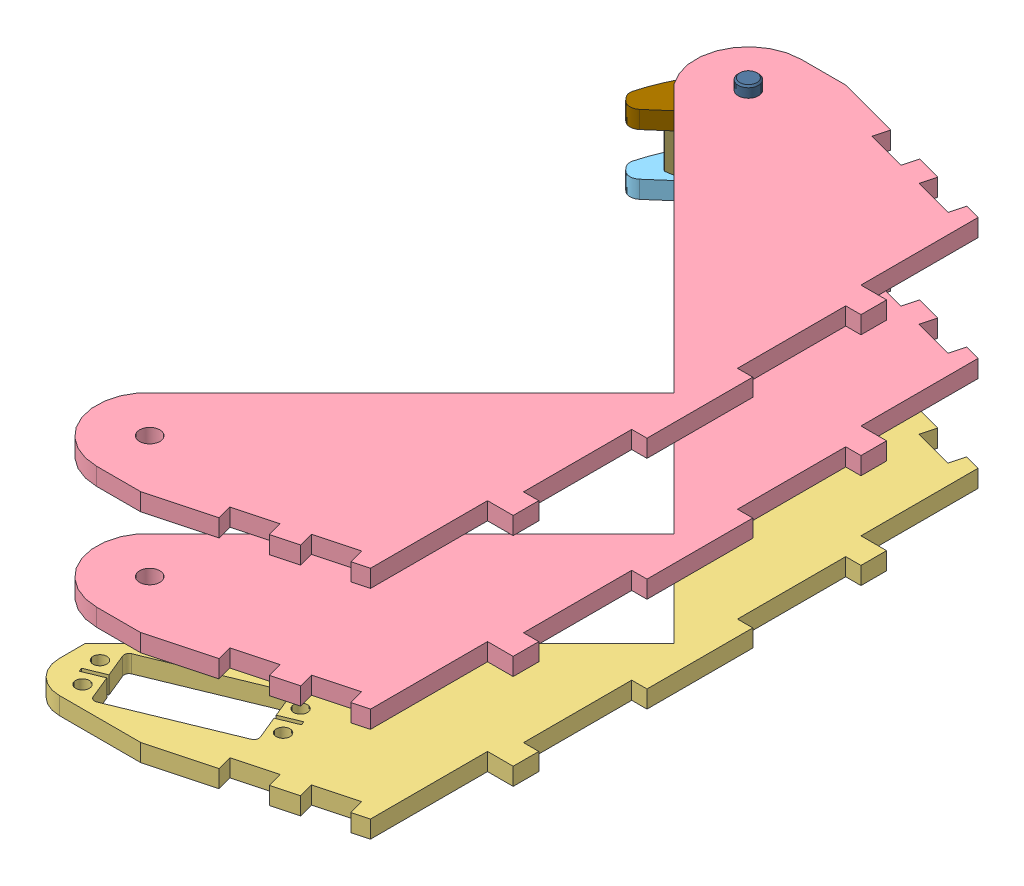
SolidWorks assembly Gripper Assm rA.01, configuration Default. Lengths in mm.
Overall size (128.06 105.71 236.15).
20 component instances, 15 part files, 50 mates.
Components (placement in the parent):
- 1718 GLYPH BLACK-1: 1718 GLYPH BLACK [Default] at (-76.2 0 0) size (152.4 152.4 152.4) (hidden)
- 1718 GLYPH BLACK-2: 1718 GLYPH BLACK [Default] at (-152.4 0 0) x (0.707107 0 0.707107) z (-0.707107 0 0.707107) size (152.4 152.4 152.4) (hidden)
- Grabber Paddle-1: Grabber Paddle [Default] at origin
- TETRIX_739197_SERVO_2012-1: TETRIX_739197_SERVO_2012 [Default] at (-7.184 35.6 -93.4511) x (-0.380109 0 0.924942) z (-0.924942 0 -0.380109) size (20 43.2 56.76)
- 8699-17-307 Gripper Mount Structure-1: 8699-17-307 Gripper Mount Structure [Default] at origin
- Tetrix Servo Hub Metal Light Duty-1: Tetrix Servo Hub Metal Light Duty [Default] at (-7.184 55.1 -93.4511) size (22 6.2 22)
- 8699-17-314 Gripper Strut ServoMnt-1: 8699-17-314 Gripper Strut ServoMnt [Default] at (63.1261 38.1 0) size (100 5.46 220)
- 8699-17-315 Gripper Strut Axle-1: 8699-17-315 Gripper Strut Axle [Default] at (63.1261 67.8 0) size (94.86 5.46 220)
- 8699-17-315 Gripper Strut Axle-2: 8699-17-315 Gripper Strut Axle [Default] at (63.1261 105.9 0) size (94.86 5.46 220)
- 8699-17-316 Gripper Right Servoed-1: 8699-17-316 Gripper Right Servoed [Default] at (-7.184 55.1 -93.4511) size (63.25 5.46 43.7)
- 90631A007 Hex Nut 6-32 Nyloc LoS-1: 90631A007 Hex Nut 6-32 Nyloc LoS [90631A007] at (-7.184 60.561 -101.4511) size (7.94 4.37 9.17)
- tetrix_739097 Screw SHC 6-32 0.50Lg-1: tetrix_739097 Screw SHC 6-32 0.50Lg [Default] at (-7.184 53.1 -101.4511) x (-1 0 0) z (0 0 1) size (5.74 16.21 5.74)
- Washer .31 id-1: Washer .31 id [Default] at (-7.184 73.261 -93.4511) size (22.17 0.71 22.17)
- 8699-17-317 rC Gripper Right Axled-3: 8699-17-317 rC Gripper Right Axled [Default] at (-7.184 73.9722 -93.4511) size (63.25 5.46 43.7)
- Washer .31 id-2: Washer .31 id [Default] at (-7.184 105.1888 -93.4511) size (22.17 0.71 22.17)
- Washer .31 id-3: Washer .31 id [Default] at (-7.184 79.4332 -93.4511) size (22.17 0.71 22.17)
- 8699-17-318 Shaft - Gripper Grooved-1: 8699-17-318 Shaft - Gripper Grooved [Default] at (-7.184 57.561 -93.4511) size (6.35 57.15 6.35)
- 8699-17-319 Grippers Dowel Conn-1: 8699-17-319 Grippers Dowel Conn [Default] at (-28.0465 60.561 -108.5448) size (15.88 13.41 15.88)
- 8699-17-324 Grippers Dowel Conn Front-1: 8699-17-324 Grippers Dowel Conn Front [Default] at (-44.5973 60.561 -115.7104) x (0.917686 0 0.397307) z (-0.397307 0 0.917686) size (15.88 13.41 15.72)
- 8699-17-317 rC Gripper Right Axled-2: 8699-17-317 rC Gripper Right Axled [Default] at (-7.184 111.361 -93.4511) x (0.997645 0 -0.068586) z (0.068586 0 0.997645) size (63.25 5.46 43.7) (hidden)
Mates (geometry in assembly coordinates):
- Coincident1: coincident aligned: plane of 1718 GLYPH BLACK-1 through (-76.2 0 0) normal (0 1 0); plane of assembly through (0 0 0) normal (0 1 0)
- Coincident2: coincident aligned: plane of 1718 GLYPH BLACK-1 through (0 0 76.2) normal (1 0 0); plane of assembly through (0 0 0) normal (1 0 0)
- Coincident3: coincident aligned: plane of 1718 GLYPH BLACK-1 through (-76.2 0 0) normal (0 0 1); plane of assembly through (0 0 0) normal (0 0 1)
- Coincident4: coincident aligned: plane of 1718 GLYPH BLACK-1 through (-76.2 152.4 0) normal (0 1 0); plane of 1718 GLYPH BLACK-2 through (-152.4 152.4 0) normal (0 1 0)
- Coincident5: coincident: point of 1718 GLYPH BLACK-2; plane of assembly
- Angle1: planar angle = 0.785398 rad aligned: plane of 1718 GLYPH BLACK-2 through (-152.4 0 0) normal (0.707107 0 0.707107); plane of assembly through (0 0 0) normal (1 0 0)
- Coincident8: coincident: plane of 1718 GLYPH BLACK-1 through (-152.4 0 -76.2) normal (-1 0 0); point of 1718 GLYPH BLACK-2
- Concentric1: concentric: cylinder of TETRIX_739197_SERVO_2012-1 through (-7.184 52.2 -93.4511) axis (0 -1 0) radius 3; point of assembly
- Coincident10: coincident aligned: plane of TETRIX_739197_SERVO_2012-1 through (-7.184 0 -90.4193) normal (0 1 0); plane of assembly through (0 0 0) normal (0 1 0)
- Coincident11: coincident anti-aligned: plane of TETRIX_739197_SERVO_2012-1 through (-7.184 48.9 -93.4511) normal (0 1 0); plane of Tetrix Servo Hub Metal Light Duty-1 through (-11.584 48.9 -93.4511) normal (0 -1 0)
- Concentric2: concentric aligned: cylinder of TETRIX_739197_SERVO_2012-1 through (-7.184 52.2 -93.4511) axis (0 -1 0) radius 3; cylinder of Tetrix Servo Hub Metal Light Duty-1 through (-7.184 55.1 -93.4511) axis (0 -1 0) radius 1.75
- Distance1: distance = 38.1 mm aligned: plane of 8699-17-314 Gripper Strut ServoMnt-1 through (63.1261 38.1 0) normal (0 1 0); plane of assembly through (0 0 0) normal (0 1 0)
- Parallel1: parallel aligned: plane of 8699-17-314 Gripper Strut ServoMnt-1 through (63.1261 38.1 0) normal (1 0 0); plane of assembly through (0 0 0) normal (1 0 0)
- Angle2: planar angle = 1.960711 rad aligned: plane of TETRIX_739197_SERVO_2012-1 through (-7.184 35.6 -93.4511) normal (-0.380109 0 0.924942); plane of assembly through (0 0 0) normal (1 0 0)
- Coincident17: coincident anti-aligned: plane of TETRIX_739197_SERVO_2012-1 through (22.288 38.1 -72.8253) normal (0 1 0); plane of 8699-17-314 Gripper Strut ServoMnt-1 through (63.1261 38.1 0) normal (0 -1 0)
- Coincident18: coincident aligned: plane of 8699-17-314 Gripper Strut ServoMnt-1 through (71.1261 43.561 -58.293) normal (1 0 0); plane of 8699-17-315 Gripper Strut Axle-1 through (71.1261 73.261 -58.293) normal (1 0 0)
- Distance2: distance = 12.7 mm anti-aligned: plane of 8699-17-315 Gripper Strut Axle-1 through (-7.184 67.8 93.4511) normal (0 -1 0); plane of Tetrix Servo Hub Metal Light Duty-1 through (-18.184 55.1 -93.4511) normal (0 1 0)
- Coincident20: coincident aligned: plane of 8699-17-314 Gripper Strut ServoMnt-1 through (-28.8739 43.561 -110) normal (0 0 -1); plane of 8699-17-315 Gripper Strut Axle-1 through (-7.184 73.261 -110) normal (0 0 -1)
- Coincident21: coincident aligned: plane of Tetrix Servo Hub Metal Light Duty-1 through (-18.184 55.1 -93.4511) normal (0 1 0); plane of 8699-17-316 Gripper Right Servoed-1 through (-7.184 55.1 -93.4511) normal (0 1 0)
- Concentric3: concentric aligned: cylinder of Tetrix Servo Hub Metal Light Duty-1 through (-7.184 55.1 -93.4511) axis (0 -1 0) radius 1.75; line of 8699-17-316 Gripper Right Servoed-1 through (-7.184 105.1 -93.4511) axis (0 -1 0)
- Parallel3: parallel aligned: plane of 8699-17-316 Gripper Right Servoed-1 through (-7.184 55.1 -93.4511) normal (1 0 0); plane of assembly through (0 0 0) normal (1 0 0)
- Coincident23: coincident aligned: plane of 8699-17-314 Gripper Strut ServoMnt-1 through (63.1261 38.1 0) normal (0 0 1); plane of assembly through (0 0 0) normal (0 0 1)
- Distance3: distance = 63.1261 mm aligned: plane of 8699-17-314 Gripper Strut ServoMnt-1 through (63.1261 38.1 0) normal (1 0 0); plane of assembly through (0 0 0) normal (1 0 0)
- Coincident25: coincident anti-aligned: plane of 8699-17-316 Gripper Right Servoed-1 through (-53.0324 60.561 -105.5885) normal (0 1 0); plane of 90631A007 Hex Nut 6-32 Nyloc LoS-1 through (-11.1528 60.561 -108.3251) normal (0 -1 0)
- Concentric4: concentric aligned: cylinder of 8699-17-316 Gripper Right Servoed-1 through (-7.184 60.561 -101.4511) axis (0 -1 0) radius 1.75; cylinder of 90631A007 Hex Nut 6-32 Nyloc LoS-1 through (-7.184 64.2752 -101.4511) axis (0 -1 0) radius 1.4103
- Coincident26: coincident anti-aligned: plane of Tetrix Servo Hub Metal Light Duty-1 through (-18.184 53.1 -93.4511) normal (0 -1 0); plane of tetrix_739097 Screw SHC 6-32 0.50Lg-1 through (-9.1906 53.1 -101.4511) normal (0 1 0)
- Concentric5: concentric aligned: cylinder of Tetrix Servo Hub Metal Light Duty-1 through (-7.184 55.1 -101.4511) axis (0 1 0) radius 1.75; cylinder of tetrix_739097 Screw SHC 6-32 0.50Lg-1 through (-7.184 49.5948 -101.4511) axis (0 1 0) radius 1.7526
- Coincident27: coincident anti-aligned: plane of 8699-17-315 Gripper Strut Axle-1 through (-7.184 73.261 93.4511) normal (0 1 0); plane of Washer .31 id-1 through (-7.184 73.261 -93.4511) normal (0 -1 0)
- Concentric6: concentric aligned: cylinder of 8699-17-315 Gripper Strut Axle-1 through (-7.184 73.261 -93.4511) axis (0 -1 0) radius 3.175; cylinder of Washer .31 id-1 through (-7.184 73.9722 -93.4511) axis (0 -1 0) radius 11.0871
- Parallel4: parallel aligned: plane of Washer .31 id-1 through (-7.184 73.261 -93.4511) normal (0 0 1); plane of assembly through (0 0 0) normal (0 0 1)
- Parallel5: parallel aligned: plane of tetrix_739097 Screw SHC 6-32 0.50Lg-1 through (-7.184 53.1 -101.4511) normal (0 0 1); plane of assembly through (0 0 0) normal (0 0 1)
- Parallel6: parallel aligned: plane of Tetrix Servo Hub Metal Light Duty-1 through (-7.184 55.1 -93.4511) normal (0 0 1); plane of assembly through (0 0 0) normal (0 0 1)
- Coincident31: coincident anti-aligned: plane of Washer .31 id-1 through (-7.184 73.9722 -93.4511) normal (0 1 0); plane of 8699-17-317 rC Gripper Right Axled-3 through (-7.184 73.9722 -93.4511) normal (0 -1 0)
- Concentric7: concentric aligned: cylinder of 8699-17-316 Gripper Right Servoed-1 through (-7.184 60.561 -93.4511) axis (0 -1 0) radius 3.175; cylinder of 8699-17-317 rC Gripper Right Axled-3 through (-7.184 79.4332 -93.4511) axis (0 -1 0) radius 3.175
- Coincident32: coincident aligned: plane of 8699-17-316 Gripper Right Servoed-1 through (-43.2596 60.561 -109.7933) normal (-0.588129 0 0.808767); plane of 8699-17-317 rC Gripper Right Axled-3 through (-43.2596 79.4332 -109.7933) normal (-0.588129 0 0.808767)
- Coincident33: coincident anti-aligned: plane of 8699-17-315 Gripper Strut Axle-2 through (-7.184 105.9 93.4511) normal (0 -1 0); plane of Washer .31 id-2 through (-7.184 105.9 -93.4511) normal (0 1 0)
- Concentric8: concentric aligned: cylinder of 8699-17-315 Gripper Strut Axle-2 through (-7.184 111.361 -93.4511) axis (0 -1 0) radius 3.175; cylinder of Washer .31 id-2 through (-7.184 105.9 -93.4511) axis (0 -1 0) radius 4.1402
- Coincident34: coincident anti-aligned: plane of 8699-17-317 rC Gripper Right Axled-3 through (-7.184 79.4332 -93.4511) normal (0 1 0); plane of Washer .31 id-3 through (-7.184 79.4332 -93.4511) normal (0 -1 0)
- Concentric9: concentric aligned: cylinder of 8699-17-317 rC Gripper Right Axled-3 through (-7.184 79.4332 -93.4511) axis (0 -1 0) radius 3.175; cylinder of Washer .31 id-3 through (-7.184 80.1444 -93.4511) axis (0 -1 0) radius 4.1402
- Distance4: distance = 3 mm anti-aligned: plane of 8699-17-318 Shaft - Gripper Grooved-1 through (-7.184 57.561 -93.4511) normal (0 -1 0); plane of 8699-17-316 Gripper Right Servoed-1 through (-53.0324 60.561 -105.5885) normal (0 1 0)
- Concentric10: concentric anti-aligned: cylinder of 8699-17-316 Gripper Right Servoed-1 through (-7.184 60.561 -93.4511) axis (0 -1 0) radius 3.175; cylinder of 8699-17-318 Shaft - Gripper Grooved-1 through (-7.184 57.561 -93.4511) axis (0 1 0) radius 3.175
- Parallel7: parallel aligned: plane of 8699-17-318 Shaft - Gripper Grooved-1 through (-7.184 57.561 -93.4511) normal (1 0 0); plane of assembly through (0 0 0) normal (1 0 0)
- Coincident37: coincident anti-aligned: plane of 8699-17-316 Gripper Right Servoed-1 through (-53.0324 60.561 -105.5885) normal (0 1 0); plane of 8699-17-319 Grippers Dowel Conn-1 through (-28.0465 60.561 -108.5448) normal (0 -1 0)
- Concentric11: concentric aligned: cylinder of 8699-17-316 Gripper Right Servoed-1 through (-28.0465 60.561 -108.5448) axis (0 -1 0) radius 1.778; cylinder of 8699-17-319 Grippers Dowel Conn-1 through (-28.0465 73.9722 -108.5448) axis (0 -1 0) radius 7.9375
- Coincident38: coincident anti-aligned: plane of 8699-17-316 Gripper Right Servoed-1 through (-53.0324 60.561 -105.5885) normal (0 1 0); plane of 8699-17-324 Grippers Dowel Conn Front-1 through (-44.5973 60.561 -115.7104) normal (0 -1 0)
- Concentric12: concentric aligned: cylinder of 8699-17-316 Gripper Right Servoed-1 through (-44.5973 60.561 -115.7104) axis (0 -1 0) radius 7.9375; cylinder of 8699-17-324 Grippers Dowel Conn Front-1 through (-44.5973 73.9722 -115.7104) axis (0 -1 0) radius 7.9375
- Parallel8: parallel anti-aligned: plane of 8699-17-316 Gripper Right Servoed-1 through (-41.4437 60.561 -122.9945) normal (0.397307 0 -0.917686); plane of 8699-17-324 Grippers Dowel Conn Front-1 through (-44.5973 60.561 -115.7104) normal (-0.397307 0 0.917686)
- Coincident39: coincident anti-aligned: plane of 8699-17-315 Gripper Strut Axle-2 through (-7.184 111.361 93.4511) normal (0 1 0); plane of 8699-17-317 rC Gripper Right Axled-2 through (-7.184 111.361 -93.4511) normal (0 -1 0)
- Concentric13: concentric anti-aligned: cylinder of 8699-17-318 Shaft - Gripper Grooved-1 through (-7.184 57.561 -93.4511) axis (0 1 0) radius 3.175; cylinder of 8699-17-317 rC Gripper Right Axled-2 through (-7.184 116.822 -93.4511) axis (0 -1 0) radius 3.175
- Coincident40: coincident: unknown of ?
